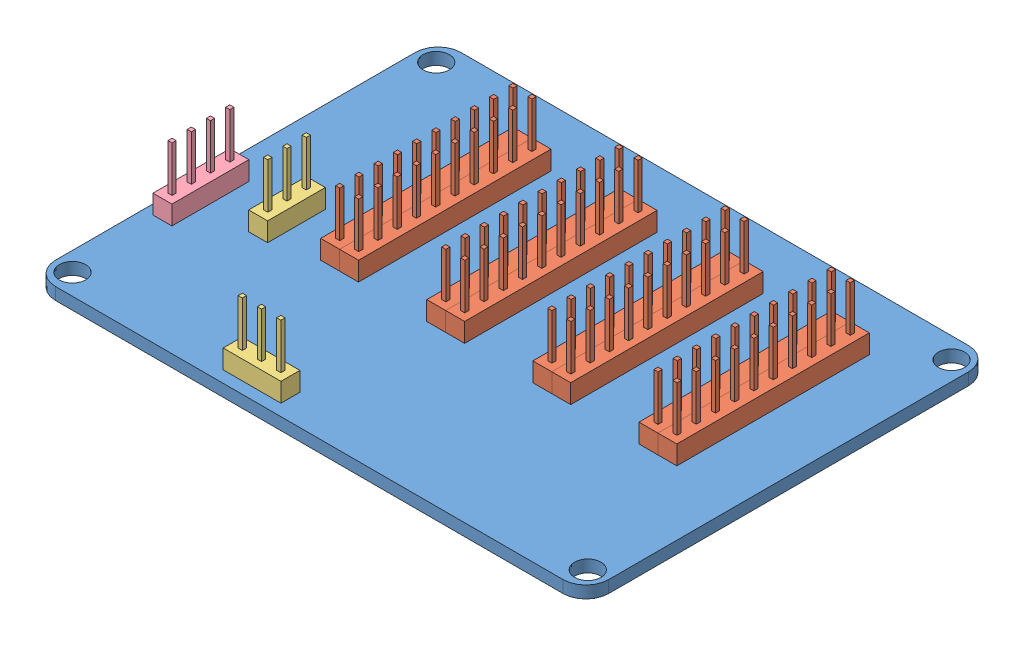
SolidWorks assembly Centipede_shield_v2, configuration Default. Lengths in mm.
Overall size (73 11.5 53.5).
8 component instances, 4 part files, 12 mates.
Components (placement in the parent):
- Centipede_shield_v2-1: Centipede_shield_v2 [Default] at origin size (73 1.6 53.5)
- header_m2x10-1: header_m2x10 [Default] at (-15.25 4.1 6.25) x (0 0 -1) z (-1 0 0) size (25.4 11.5 5)
- header_m2x10-2: header_m2x10 [Default] at (-1.25 4.1 6.25) x (0 0 -1) z (-1 0 0) size (25.4 11.5 5)
- header_m2x10-3: header_m2x10 [Default] at (12.75 4.1 6.25) x (0 0 -1) z (-1 0 0) size (25.4 11.5 5)
- header_m2x10-4: header_m2x10 [Default] at (26.75 4.1 6.25) x (0 0 -1) z (-1 0 0) size (25.4 11.5 5)
- header_m3-1: header_m3 [Default] at (-25.75 4.1 7.75) x (0 0 -1) z (-1 0 0) size (7.62 11.5 2.5)
- header_m3-2: header_m3 [Default] at (-5.28 4.1 23.96) x (-1 0 0) z (0 0 1) size (7.62 11.5 2.5)
- header_m4-1: header_m4 [Default] at (-33.98 4.1 12.15) x (0 0 -1) z (-1 0 0) size (10.16 11.5 2.5)
Mates (geometry in assembly coordinates):
- Coincident1: coincident anti-aligned: plane of Centipede_shield_v2-1 through (0 1.6 0) normal (0 1 0); plane of header_m2x10-1 through (-16.5 1.6 6.25) normal (0 -1 0)
- Distance1: distance = 17.5 mm aligned: plane of header_m2x10-1 through (-19 4.1 6.25) normal (-1 0 0); plane of Centipede_shield_v2-1 through (-36.5 1.6 26.75) normal (-1 0 0)
- Distance2: distance = 7.6 mm aligned: plane of header_m2x10-1 through (-16.5 4.1 -19.15) normal (0 0 -1); plane of Centipede_shield_v2-1 through (36.5 1.6 -26.75) normal (0 0 -1)
- Coincident4: coincident: plane of Centipede_shield_v2-1 through (0 1.6 0) normal (0 1 0); plane of header_m3-1 through (-27 1.6 7.6986) normal (0 -1 0)
- Coincident5: coincident: plane of Centipede_shield_v2-1 through (0 1.6 0) normal (0 1 0); plane of header_m3-2 through (-5.28 1.6 25.21) normal (0 -1 0)
- Coincident6: coincident anti-aligned: plane of Centipede_shield_v2-1 through (0 1.6 0) normal (0 1 0); plane of header_m4-1 through (-35.23 1.6 12.15) normal (0 -1 0)
- Distance3: distance = 1.27 mm aligned: plane of header_m4-1 through (-35.23 4.1 12.15) normal (-1 0 0); plane of Centipede_shield_v2-1 through (-36.5 1.6 26.75) normal (-1 0 0)
- Distance4: distance = 14.6 mm aligned: plane of Centipede_shield_v2-1 through (36.5 1.6 26.75) normal (0 0 1); plane of header_m4-1 through (-35.23 4.1 12.15) normal (0 0 1)
- Distance5: distance = 1.54 mm: plane of header_m3-2 through (-5.28 4.1 25.21) normal (0 0 1); plane of Centipede_shield_v2-1 through (36.5 1.6 26.75) normal (0 0 1)
- Distance6: distance = 23.6 mm aligned: plane of header_m3-2 through (-12.9 4.1 25.21) normal (-1 0 0); plane of Centipede_shield_v2-1 through (-36.5 1.6 26.75) normal (-1 0 0)
- Distance7: distance = 9.5 mm: plane of header_m3-1 through (-27 4.1 7.75) normal (-1 0 0); plane of Centipede_shield_v2-1 through (-36.5 1.6 26.75) normal (-1 0 0)
- Distance8: distance = 19 mm aligned: plane of header_m3-1 through (-27 4.1 7.75) normal (0 0 1); plane of Centipede_shield_v2-1 through (36.5 1.6 26.75) normal (0 0 1)
